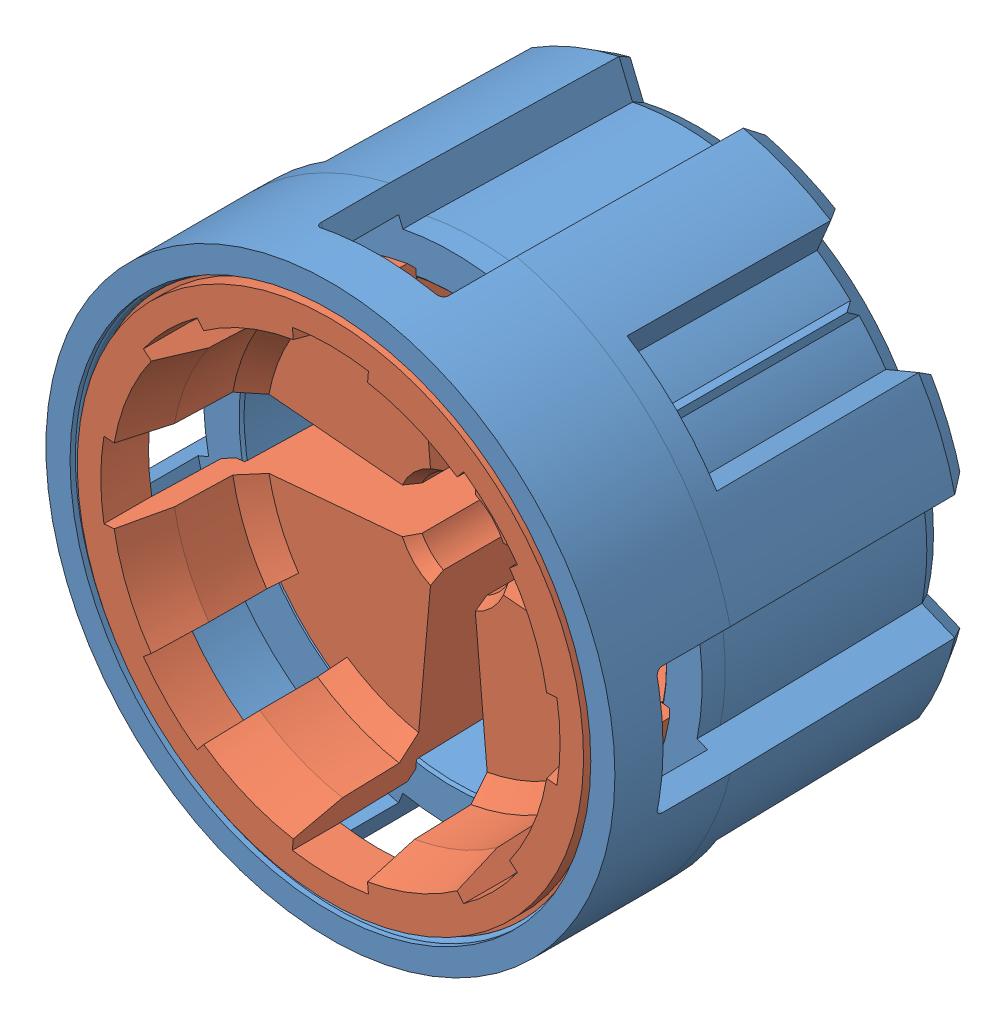
SolidWorks assembly Center Insert Assembly, configuration Default. Lengths in mm.
Overall size (11.8 11.8 7.62).
2 component instances, 2 part files, 3 mates.
Components (placement in the parent):
- CENTER INSERT WITH 8 SPLINES-1: CENTER INSERT WITH 8 SPLINES [Default] at origin size (11.8 11.8 7.62)
- CENTER INSERT-1: CENTER INSERT [Default] at (0 0 -3.81) size (10.8 10.8 7.62)
Mates (geometry in assembly coordinates):
- Coincident1: coordinate: point of CENTER INSERT WITH 8 SPLINES-1; point of assembly
- Concentric1: concentric aligned: cone of CENTER INSERT WITH 8 SPLINES-1 through (0 0 -2.54) axis (0 0 -1); cone of CENTER INSERT-1 through (0 0 -7.62) axis (0 0 -1)
- Coincident2: coincident aligned: plane of CENTER INSERT WITH 8 SPLINES-1 through (0 0 -7.62) normal (0 0 -1); plane of CENTER INSERT-1 through (0 4.2276 -7.62) normal (0 0 -1)
